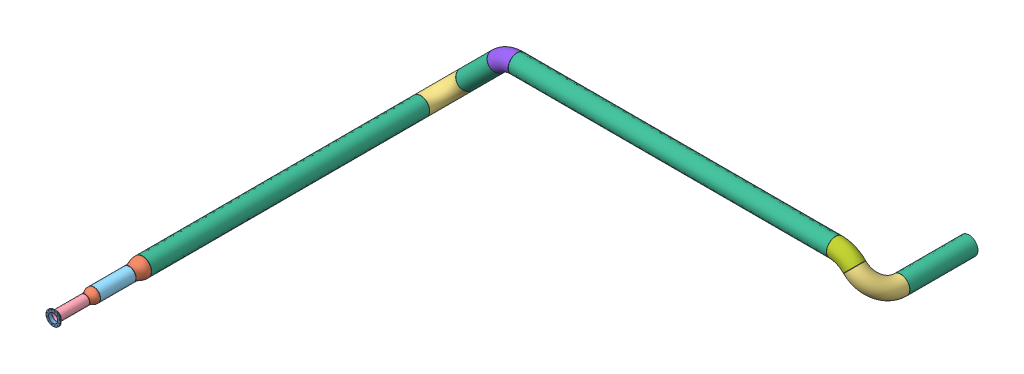
SolidWorks assembly Air From Compressor - 600 GA 1101 CS-PN10, configuration Default. Lengths in mm.
Overall size (15235.37 2955.51 16520.01).
13 component instances, 8 part files, 2 mates.
Components (placement in the parent):
- welding neck flange-1: welding neck flange [WNeck Flange 150-NPS12] at (-8928.1015 3446 -2087.526) size (482.6 482.6 124.31)
- reducer-1: reducer [REDUCER 18 x 12] at (-8928.1015 3446 -3459.7413) x (0 0 1) z (0 1 0) size (324.8 457.2 457.2)
- reducer-2: reducer [REDUCER 24 x 18] at (-8928.1015 3446 -5106.5595) x (0 0 1) z (0 1 0) size (477.2 609.6 609.6)
- 90deg LR Inch Elbow-1: 90deg LR Inch Elbow [90L LR Inch 24 Sch60] at (-8281.523 4092.5784 -14480.7301) x (0 0 1) z (0.707107 -0.707107 0) size (1229.29 1229.29 609.8)
- 12inSchedule60-routeAssy5-SKLOP DISPOZICIJE-1: 12inSchedule60-routeAssy5-SKLOP DISPOZICIJE [12 in, Schedule 60, 1] at (-8928.1015 3446 -2200.302) x (0.707107 0.707107 0) z (0 0 -1) size (323.85 323.85 954.64)
- 18inSchedule60-routeAssy5-SKLOP DISPOZICIJE-1: 18inSchedule60-routeAssy5-SKLOP DISPOZICIJE [18 in, Schedule 60] at (-8928.1015 3446 -3459.7413) x (0.707107 0.707107 0) z (0 0 -1) size (457.2 457.2 1189.62)
- 24inSchedule60_6-routeAssy5-SKLOP DISPOZICIJE-1: 24inSchedule60_6-routeAssy5-SKLOP DISPOZICIJE [24 in, Schedule 60] at (-8928.1015 3446 -5106.5595) x (0.707107 0.707107 0) z (0 0 -1) size (609.6 609.6 9374.17)
- 24inSchedule60_6-routeAssy5-SKLOP DISPOZICIJE-2: 24inSchedule60_6-routeAssy5-SKLOP DISPOZICIJE [24 in, Schedule 60, 1] at (-8281.523 4092.5784 -15395.1301) x (0.57735 -0.57735 0.57735) z (0.707107 0.707107 0) size (609.6 609.6 1492)
- 24inSchedule60_6-routeAssy5-SKLOP DISPOZICIJE-3: 24inSchedule60_6-routeAssy5-SKLOP DISPOZICIJE [24 in, Schedule 60, 2] at (-6579.9432 5415.4014 -15395.1301) x (0 0.707107 0.707107) z (1 0 0) size (609.6 609.6 10731.68)
- 24inSchedule60_6-routeAssy5-SKLOP DISPOZICIJE-5: 24inSchedule60_6-routeAssy5-SKLOP DISPOZICIJE [24 in, Schedule 60, 4] at (5444.8985 4501 -16309.5301) x (0.707107 0.707107 0) z (0 0 -1) size (609.6 609.6 2296.47)
- 90deg lr inch elbow_Local1-routeAssy5-SKLOP DISPOZICIJE-5: 90deg lr inch elbow_Local1-routeAssy5-SKLOP DISPOZICIJE [D=24in, A=45deg, R=36in] at (4151.7402 4501.0014 -15395.1301) x (-0.707107 -0.707107 0) z (0 0 -1) size (786.56 868.65 609.8)
- 90deg LR Inch Elbow-6: 90deg LR Inch Elbow [90L LR Inch 24 Sch60] at (4798.3201 5147.5784 -16309.5301) x (-0.707107 0.707107 0) z (0.707107 0.707107 0) size (1229.29 1229.29 609.8)
- 90deg lr inch elbow_Local2-routeAssy5-SKLOP DISPOZICIJE-7: 90deg lr inch elbow_Local2-routeAssy5-SKLOP DISPOZICIJE [D=24in, A=45deg, R=36in] at (-6579.9432 4501.0014 -15395.1301) x (0 -1 0) z (0 0 -1) size (786.56 868.65 609.8)
Mates (geometry in assembly coordinates):
- Concentric1: concentric anti-aligned: cylinder of ? through (-8928.1015 3446 -2086.002) axis (0 0 1) radius 142.4; cylinder of welding neck flange-1 through (-8928.1015 3446 -2086.002) axis (0 0 -1) radius 182.626
- Coincident1: coincident anti-aligned: plane of ? through (-8928.1015 3446 -2086.002) normal (0 0 -1); plane of welding neck flange-1 through (-8928.1015 3446 -2086.002) normal (0 0 1)
